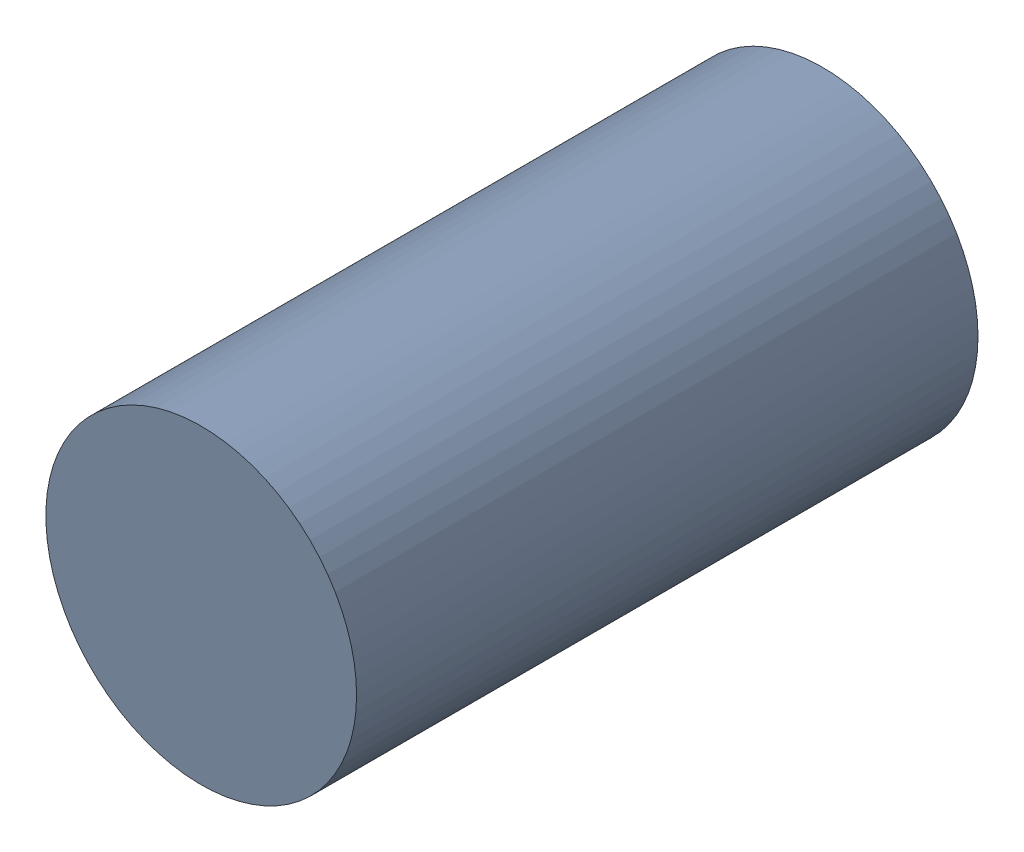
SolidWorks assembly MH10_3.step, configuration Default. Lengths in mm.
Overall size (1 1 2).
2 component instances, 1 part files, 0 mates.
Components (placement in the parent):
- 9228463120_2.step-2: 9228463120_2.step [Default] at (74.375 92.2947 -1.5) size (1 1 2)
  - Cylinder_4.step-7: Cylinder_4.step [Default] at origin size (1 1 2)
